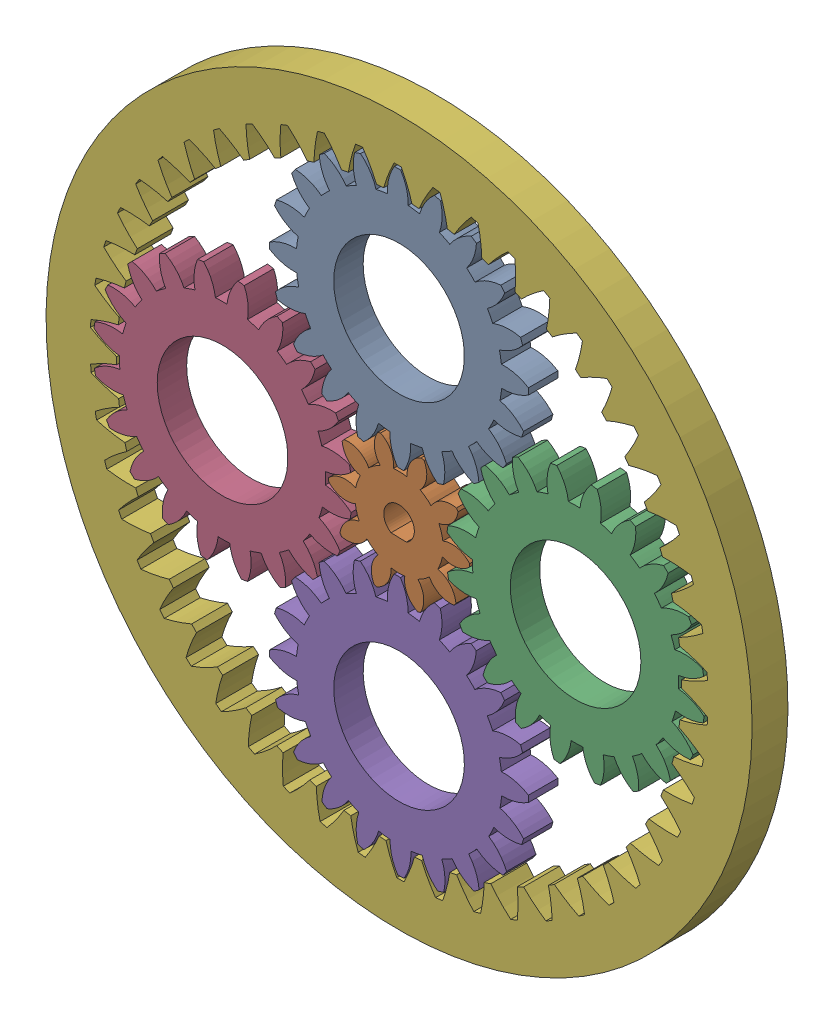
SolidWorks assembly Assem1, configuration Default. Lengths in mm.
Overall size (139.94 139.94 6.1).
6 component instances, 3 part files, 17 mates.
Components (placement in the parent):
- part1_planet_ext-2: part1_planet_ext [Metric - Spur gear 2M 20T 20PA 5FW ---S20N75H50L1N] at (0 30 0) x (0 0 1) z (-0.443118 -0.896464 0) size (5 43.61 43.61)
- part2_sungear-3: part2_sungear [Metric - Spur gear 2M 10T 20PA 5FW ---S10N75H50L1N] x (0 0 1) z (0.999628 -0.027288 0) size (5 22.98 24)
- part1_planet_ext-3: part1_planet_ext [Metric - Spur gear 2M 20T 20PA 5FW ---S20N75H50L1N] at (30 0 0) x (0 0 1) z (-0.955086 0.296329 0) size (5 43.61 43.61)
- part1_planet_ext-4: part1_planet_ext [Metric - Spur gear 2M 20T 20PA 5FW ---S20N75H50L1N] at (-30 0 0) x (0 0 1) z (-0.816619 0.577177 0) size (5 43.61 43.61)
- part1_planet_ext-5: part1_planet_ext [Metric - Spur gear 2M 20T 20PA 5FW ---S20N75H50L1N] at (0 -30 0) x (0 0 1) z (-0.897119 0.441788 0) size (5 43.61 43.61)
- part3_int_spur-3: part3_int_spur [Metric - Internal spur gear 2M 50T 20PA 6.1FW ---S50S120OD 1AF] at (0 0 5) x (0 0 -1) z (-0.183106 -0.983093 0) size (6.1 120 120)
Mates (geometry in assembly coordinates):
- Concentric4: concentric anti-aligned: circle of part2_sungear-3
- Concentric5: concentric anti-aligned: cylinder of part1_planet_ext-2 through (0 30 10) axis (0 0 -1) radius 11.1
- Coincident2: coincident anti-aligned: plane of part2_sungear-3 through (0 0 0) normal (0 0 -1)
- Coincident3: coincident aligned: plane of part1_planet_ext-2 through (0 30 0) normal (0 0 -1); plane of part2_sungear-3 through (0 0 0) normal (0 0 -1)
- Coincident5: coincident aligned: plane of part1_planet_ext-2 through (0 30 5) normal (0 0 1); plane of part1_planet_ext-3 through (30 0 5) normal (0 0 1)
- Concentric6: concentric anti-aligned: cylinder of part1_planet_ext-3 through (30 0 10) axis (0 0 -1) radius 11.1
- Concentric7: concentric anti-aligned: cylinder of part1_planet_ext-4 through (-30 0 10) axis (0 0 -1) radius 11.1
- Coincident6: coincident aligned: plane of part1_planet_ext-2 through (0 30 5) normal (0 0 1); plane of part1_planet_ext-4 through (-30 0 5) normal (0 0 1)
- Coincident8: coincident aligned: plane of part1_planet_ext-4 through (-30 0 5) normal (0 0 1); plane of part1_planet_ext-5 through (0 -30 5) normal (0 0 1)
- Concentric8: concentric anti-aligned: cylinder of part1_planet_ext-5 through (0 -30 10) axis (0 0 -1) radius 11.1
- GearMate3: gear = 10 : 20 mm: cylinder of part1_planet_ext-2 through (0 30 10) axis (0 0 -1) radius 11.1; cylinder of part2_sungear-3 through (0 0 10) axis (0 0 -1) radius 2.6
- GearMate4: gear = 10 : 20 mm: cylinder of part1_planet_ext-4 through (-30 0 10) axis (0 0 -1) radius 11.1; cylinder of part2_sungear-3 through (0 0 10) axis (0 0 -1) radius 2.6
- GearMate5: gear = 10 : 20 mm: cylinder of part1_planet_ext-5 through (0 -30 10) axis (0 0 -1) radius 11.1; cylinder of part2_sungear-3 through (0 0 10) axis (0 0 -1) radius 2.6
- GearMate6: gear = 10 : 20 mm: cylinder of part1_planet_ext-3 through (30 0 10) axis (0 0 -1) radius 11.1; cylinder of part2_sungear-3 through (0 0 10) axis (0 0 -1) radius 2.6
- Concentric15: concentric aligned: cylinder of part3_int_spur-3 through (0 0 15) axis (0 0 1) radius 60
- Coincident12: coincident aligned: plane of part1_planet_ext-2 through (0 30 5) normal (0 0 1); plane of part3_int_spur-3 through (8.7891 47.1885 5) normal (0 0 1)
- GearMate8: gear = 50 : 20 mm: cylinder of part1_planet_ext-2 through (0 30 10) axis (0 0 -1) radius 11.1; cylinder of part3_int_spur-3 through (0 0 15) axis (0 0 1) radius 60
